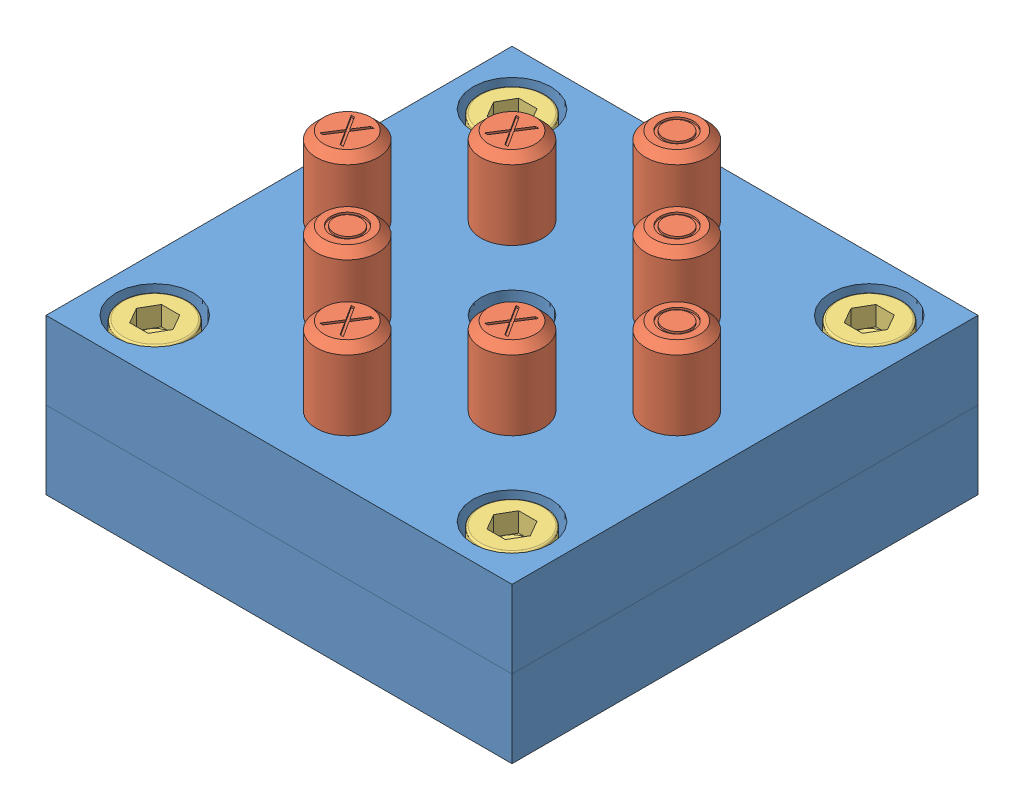
SolidWorks assembly Tic Tac Toe, configuration Predeterminado. Lengths in mm.
Overall size (60 30 60).
14 component instances, 3 part files, 27 mates.
Components (placement in the parent):
- Base-tictactoe-1: Base-tictactoe [Bottom] at (-1.1772 -7.6961 60) size (60 10 60)
- Base-tictactoe-2: Base-tictactoe [Top] at (-1.1772 2.3039 60) size (60 10 60)
- Shaft-1: Shaft [Shaft-X] at (-22.3904 2.3039 60) size (8 20 8)
- Shaft-2: Shaft [Shaft-X] at (-1.1772 2.3039 81.2132) size (8 20 8)
- Shaft-3: Shaft [Shaft-X] at (9.4294 2.3039 70.6066) size (8 20 8)
- Shaft-4: Shaft [Shaft-X] at (-11.7838 2.3039 49.3934) size (8 20 8)
- Shaft-5: Shaft [Shaft-O] at (-11.7838 2.3039 70.6066) size (8 20 8)
- Shaft-6: Shaft [Shaft-O] at (20.036 2.3039 60) size (8 20 8)
- Shaft-7: Shaft [Shaft-O] at (9.4294 2.3039 49.3934) size (8 20 8)
- Shaft-8: Shaft [Shaft-O] at (-1.1772 2.3039 38.7868) size (8 20 8)
- socket head cap screw_iso-3: socket head cap screw_iso [ISO 4762 M5 x 10 --- 10C] at (-24.1772 11.9039 37) x (0 -1 0) z (0 0 1) size (15 8.5 8.5)
- socket head cap screw_iso-4: socket head cap screw_iso [ISO 4762 M5 x 10 --- 10C] at (21.8228 11.9039 37) x (0 -1 0) z (0 0 1) size (15 8.5 8.5)
- socket head cap screw_iso-5: socket head cap screw_iso [ISO 4762 M5 x 10 --- 10C] at (21.8228 11.9039 83) x (0 -1 0) z (0 0 1) size (15 8.5 8.5)
- socket head cap screw_iso-6: socket head cap screw_iso [ISO 4762 M5 x 10 --- 10C] at (-24.1772 11.9039 83) x (0 -1 0) z (0 0 1) size (15 8.5 8.5)
Mates (geometry in assembly coordinates):
- Coincidente1: coincident aligned: plane of Base-tictactoe-1 through (-31.1772 2.3039 90) normal (0 0 1); plane of Base-tictactoe-2 through (-31.1772 12.3039 90) normal (0 0 1)
- Coincidente2: coincident aligned: plane of Base-tictactoe-1 through (28.8228 2.3039 30) normal (1 0 0); plane of Base-tictactoe-2 through (28.8228 12.3039 30) normal (1 0 0)
- Coincidente3: coincident anti-aligned: plane of Base-tictactoe-1 through (-1.1772 2.3039 60) normal (0 1 0); plane of Base-tictactoe-2 through (-1.1772 2.3039 60) normal (0 -1 0)
- Concéntrica10: concentric anti-aligned: cylinder of Base-tictactoe-2 through (-22.3904 2.3039 60) axis (0 1 0) radius 4; cylinder of Shaft-1 through (-22.3904 22.3039 60) axis (0 -1 0) radius 4
- Concéntrica11: concentric anti-aligned: cylinder of Base-tictactoe-2 through (-11.7838 2.3039 70.6066) axis (0 1 0) radius 4; cylinder of Shaft-5 through (-11.7838 22.3039 70.6066) axis (0 -1 0) radius 4
- Concéntrica12: concentric anti-aligned: cylinder of Base-tictactoe-2 through (-1.1772 2.3039 81.2132) axis (0 1 0) radius 4; cylinder of Shaft-2 through (-1.1772 22.3039 81.2132) axis (0 -1 0) radius 4
- Concéntrica13: concentric anti-aligned: cylinder of Base-tictactoe-2 through (9.4294 2.3039 70.6066) axis (0 1 0) radius 4; cylinder of Shaft-3 through (9.4294 22.3039 70.6066) axis (0 -1 0) radius 4
- Concéntrica14: concentric anti-aligned: cylinder of Base-tictactoe-2 through (20.036 2.3039 60) axis (0 1 0) radius 4; cylinder of Shaft-6 through (20.036 22.3039 60) axis (0 -1 0) radius 4
- Concéntrica15: concentric anti-aligned: cylinder of Base-tictactoe-2 through (9.4294 2.3039 49.3934) axis (0 1 0) radius 4; cylinder of Shaft-7 through (9.4294 22.3039 49.3934) axis (0 -1 0) radius 4
- Concéntrica16: concentric anti-aligned: cylinder of Base-tictactoe-2 through (-1.1772 2.3039 38.7868) axis (0 1 0) radius 4; cylinder of Shaft-8 through (-1.1772 22.3039 38.7868) axis (0 -1 0) radius 4
- Concéntrica17: concentric anti-aligned: cylinder of Base-tictactoe-2 through (-11.7838 2.3039 49.3934) axis (0 1 0) radius 4; cylinder of Shaft-4 through (-11.7838 22.3039 49.3934) axis (0 -1 0) radius 4
- Coincidente4: coincident anti-aligned: plane of Base-tictactoe-1 through (-1.1772 2.3039 60) normal (0 1 0); circle of Shaft-8
- Coincidente5: coincident anti-aligned: plane of Base-tictactoe-1 through (-1.1772 2.3039 60) normal (0 1 0); circle of Shaft-4
- Coincidente6: coincident anti-aligned: plane of Base-tictactoe-1 through (-1.1772 2.3039 60) normal (0 1 0); plane of Shaft-1 through (-22.3904 2.3039 60) normal (0 -1 0)
- Coincidente7: coincident anti-aligned: plane of Base-tictactoe-1 through (-1.1772 2.3039 60) normal (0 1 0); plane of Shaft-7 through (9.4294 2.3039 49.3934) normal (0 -1 0)
- Coincidente8: coincident anti-aligned: plane of Base-tictactoe-1 through (-1.1772 2.3039 60) normal (0 1 0); plane of Shaft-6 through (20.036 2.3039 60) normal (0 -1 0)
- Coincidente9: coincident anti-aligned: plane of Base-tictactoe-1 through (-1.1772 2.3039 60) normal (0 1 0); plane of Shaft-5 through (-11.7838 2.3039 70.6066) normal (0 -1 0)
- Coincidente10: coincident anti-aligned: plane of Base-tictactoe-1 through (-1.1772 2.3039 60) normal (0 1 0); plane of Shaft-2 through (-1.1772 2.3039 81.2132) normal (0 -1 0)
- Coincidente11: coincident anti-aligned: plane of Base-tictactoe-1 through (-1.1772 2.3039 60) normal (0 1 0); plane of Shaft-3 through (9.4294 2.3039 70.6066) normal (0 -1 0)
- Concéntrica18: concentric aligned: cylinder of Base-tictactoe-2 through (-24.1772 12.3039 37) axis (0 1 0) radius 5; cylinder of socket head cap screw_iso-3 through (-24.1772 43.6539 37) axis (0 1 0) radius 4.25
- Coincidente12: coincident anti-aligned: plane of Base-tictactoe-2 through (-21.4272 6.9039 37) normal (0 1 0); plane of socket head cap screw_iso-3 through (-19.9272 6.9039 37) normal (0 -1 0)
- Concéntrica19: concentric aligned: cylinder of Base-tictactoe-2 through (21.8228 12.3039 37) axis (0 1 0) radius 2.75; cylinder of socket head cap screw_iso-4 through (21.8228 43.6539 37) axis (0 1 0) radius 4.25
- Coincidente13: coincident anti-aligned: plane of Base-tictactoe-2 through (24.5728 6.9039 37) normal (0 1 0); plane of socket head cap screw_iso-4 through (26.0728 6.9039 37) normal (0 -1 0)
- Concéntrica20: concentric aligned: cylinder of Base-tictactoe-2 through (21.8228 12.3039 83) axis (0 1 0) radius 2.75; cylinder of socket head cap screw_iso-5 through (21.8228 43.6539 83) axis (0 1 0) radius 4.25
- Coincidente14: coincident anti-aligned: plane of Base-tictactoe-2 through (24.5728 6.9039 83) normal (0 1 0); plane of socket head cap screw_iso-5 through (26.0728 6.9039 83) normal (0 -1 0)
- Concéntrica21: concentric aligned: cylinder of Base-tictactoe-2 through (-24.1772 12.3039 83) axis (0 1 0) radius 5; cylinder of socket head cap screw_iso-6 through (-24.1772 43.6539 83) axis (0 1 0) radius 4.25
- Coincidente15: coincident anti-aligned: plane of Base-tictactoe-2 through (-21.4272 6.9039 83) normal (0 1 0); plane of socket head cap screw_iso-6 through (-19.9272 6.9039 83) normal (0 -1 0)
